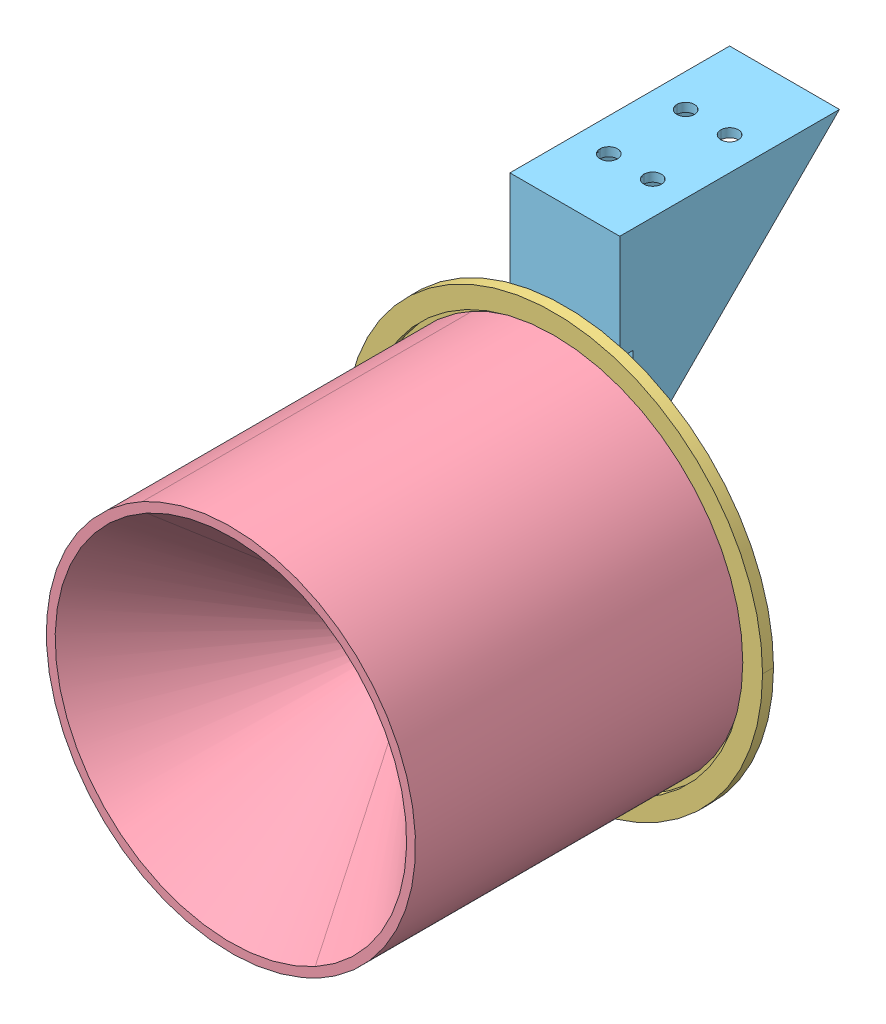
SolidWorks assembly rain_sensor_solidworks, configuration Default. Lengths in mm.
Overall size (190 230 252).
6 component instances, 5 part files, 0 mates.
Components (placement in the parent):
- assemblagereduit.CATProduct-1: assemblagereduit.CATProduct [Default] at origin size (190 230 252)
  - supportV2.CATPart-1: supportV2.CATPart [Default] at origin size (112 95 65)
  - spoonV2.CATPart-1: spoonV2.CATPart [Default] at (-0.913 17.5 25.602) x (0 -1 0) z (-0.331106 0 0.943593) size (49 108.76 30.11)
  - baseV2.CATPart-1: baseV2.CATPart [Default] at (0 0 -5) size (190 190 11)
  - boxV2.CATPart-1: boxV2.CATPart [Default] at (0 0 147) size (168.07 168.28 156)
  - mat.CATPart-1: mat.CATPart [Default] at (-25 135 -5) size (50 210 100)
